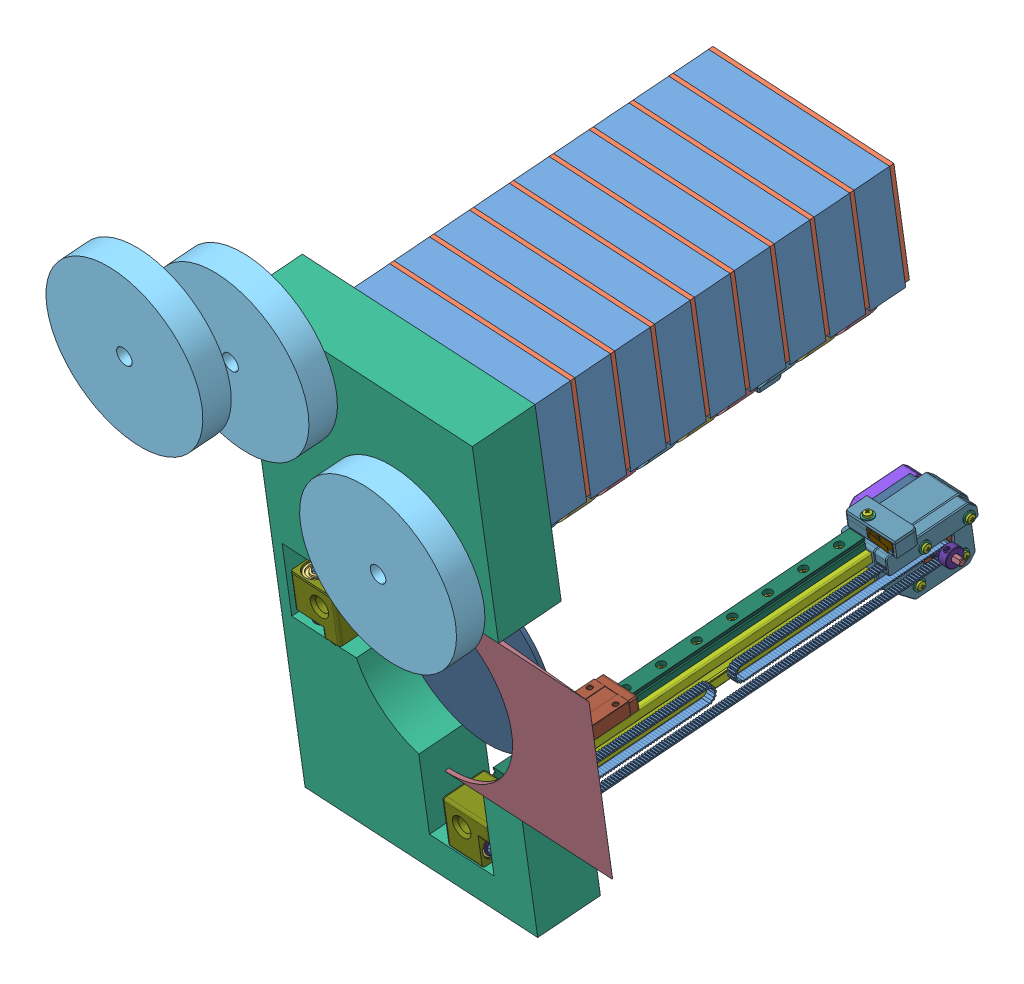
SolidWorks assembly SYSTEM2, configuration Default. Lengths in mm.
Overall size (315.85 484.95 561.42).
165 component instances, 31 part files, 110 mates.
Components (placement in the parent):
- Cakeholder-2: Cakeholder [Default] at (-409.943 623.3582 192.3225) x (0.998594 -0.003676 0.05288) z (-0.05288 -0.138263 0.988983) size (140 83.09 25)
- Cakeholder-3: Cakeholder [Default] at (-404.0205 638.8436 81.5565) x (0.998594 -0.003676 0.05288) z (-0.05288 -0.138263 0.988983) size (140 83.09 25)
- Cakeholder-4: Cakeholder [Default] at (-406.9818 631.1009 136.9395) x (0.998594 -0.003676 0.05288) z (-0.05288 -0.138263 0.988983) size (140 83.09 25)
- Cakeholder-5: Cakeholder [Default] at (-398.098 654.3291 -29.2096) x (0.998594 -0.003676 0.05288) z (-0.05288 -0.138263 0.988983) size (140 83.09 25)
- Cakeholder-6: Cakeholder [Default] at (-408.4624 627.2296 164.631) x (0.998594 -0.003676 0.05288) z (-0.05288 -0.138263 0.988983) size (140 83.09 25)
- Cakeholder-7: Cakeholder [Default] at (-405.5012 634.9723 109.248) x (0.998594 -0.003676 0.05288) z (-0.05288 -0.138263 0.988983) size (140 83.09 25)
- Cakeholder-8: Cakeholder [Default] at (-399.5786 650.4577 -1.5181) x (0.998594 -0.003676 0.05288) z (-0.05288 -0.138263 0.988983) size (140 83.09 25)
- Cakeholder-9: Cakeholder [Default] at (-401.0593 646.5864 26.1734) x (0.998594 -0.003676 0.05288) z (-0.05288 -0.138263 0.988983) size (140 83.09 25)
- Cakeholder-10: Cakeholder [Default] at (-402.5399 642.715 53.8649) x (0.998594 -0.003676 0.05288) z (-0.05288 -0.138263 0.988983) size (140 83.09 25)
- isolation-1: isolation [Default] at (-479.9507 695.3383 195.6089) x (0.998594 -0.003676 0.05288) z (-0.05288 -0.138263 0.988983) size (140 80 3)
- isolation-2: isolation [Default] at (-478.47 699.2097 167.9174) x (0.998594 -0.003676 0.05288) z (-0.05288 -0.138263 0.988983) size (140 80 3)
- isolation-3: isolation [Default] at (-476.9894 703.081 140.2259) x (0.998594 -0.003676 0.05288) z (-0.05288 -0.138263 0.988983) size (140 80 3)
- isolation-4: isolation [Default] at (-475.5088 706.9524 112.5344) x (0.998594 -0.003676 0.05288) z (-0.05288 -0.138263 0.988983) size (140 80 3)
- isolation-5: isolation [Default] at (-328.0084 646.5634 -29.5811) x (-0.998594 0.003676 -0.05288) z (-0.05288 -0.138263 0.988983) size (140 80 3)
- isolation-6: isolation [Default] at (-474.0281 710.8237 84.8429) x (0.998594 -0.003676 0.05288) z (-0.05288 -0.138263 0.988983) size (140 80 3)
- isolation-7: isolation [Default] at (-472.5475 714.6951 57.1513) x (0.998594 -0.003676 0.05288) z (-0.05288 -0.138263 0.988983) size (140 80 3)
- isolation-8: isolation [Default] at (-471.0669 718.5665 29.4598) x (0.998594 -0.003676 0.05288) z (-0.05288 -0.138263 0.988983) size (140 80 3)
- isolation-9: isolation [Default] at (-469.5863 722.4378 1.7683) x (0.998594 -0.003676 0.05288) z (-0.05288 -0.138263 0.988983) size (140 80 3)
- cream_yellow-1: cream_yellow [Default] at (-408.7268 626.5383 169.5759) x (0.998594 -0.003676 0.05288) z (-0.05288 -0.138263 0.988983) size (120 120 20)
- Icing_pink-1: Icing_pink [Default] at (-407.2462 630.4096 141.8844) x (0.998594 -0.003676 0.05288) z (-0.05288 -0.138263 0.988983) size (120 120 20)
- sponge_brown-1: sponge_brown [Default] at (-410.2074 622.6669 197.2675) x (0.992993 0.097531 0.066729) z (-0.05288 -0.138263 0.988983) size (120 120 20)
- cream_yellow-2: cream_yellow [Default] at (-404.2849 638.1523 86.5014) x (0.981304 0.176336 0.077121) z (-0.05288 -0.138263 0.988983) size (120 120 20)
- Icing_pink-2: Icing_pink [Default] at (-402.8043 642.0237 58.8099) x (0.983044 -0.181339 0.02721) z (-0.05288 -0.138263 0.988983) size (120 120 20)
- sponge_brown-2: sponge_brown [Default] at (-401.3237 645.8951 31.1183) x (0.832811 -0.552589 -0.032724) z (-0.05288 -0.138263 0.988983) size (120 120 20)
- cream_yellow-3: cream_yellow [Default] at (-399.843 649.7664 3.4268) x (0.998594 -0.003676 0.05288) z (-0.05288 -0.138263 0.988983) size (120 120 20)
- Icing_pink-3: Icing_pink [Default] at (-398.3624 653.6378 -24.2647) x (-0.229057 0.965642 0.122752) z (-0.05288 -0.138263 0.988983) size (120 120 20)
- sponge_brown-3: sponge_brown [Default] at (-405.7656 634.281 114.1929) x (0.916532 0.386462 0.103034) z (-0.05288 -0.138263 0.988983) size (120 120 20)
- base-2: base [Default] at (-384.5565 489.403 244.7212) x (0.003676 -0.990389 -0.138263) z (0.05288 0.138263 -0.988983) size (337 180 44)
- Assem1-2: Assem1 [По умолчанию] at (-489.5964 495.154 221.7084) x (-0.003676 0.990389 0.138263) z (0.05288 0.138263 -0.988983) size (62 62.45 345.25)
  - rsi_2020_274-1: rsi_2020_274 [По умолчанию] at origin size (20 20 274)
  - 17HM15-0904S-1: 17HM15-0904S [По умолчанию] at (30 -11.15 303.15) x (0 0 -1) z (0 1 0) size (42.3 62 42.3)
    - nema17_bottom_40mm-1: nema17_bottom_40mm [По умолчанию] at origin size (42 12 42)
    - radial ball bearing_68_din-1: radial ball bearing_68_din [DIN 625 - 625 - 8,SI,NC,8_68] at (0 5 0) x (0 -1 0) z (0 0 1) size (5 16 16)
    - nema17_middle_40mm-1: nema17_middle_40mm [По умолчанию] at (0 8.5 0) size (42.3 23.5 42.3)
    - nema17_top_40mm-1: nema17_top_40mm [По умолчанию] at (0 32 0) size (42.3 12.6 42.3)
    - radial ball bearing_68_din-3: radial ball bearing_68_din [DIN 625 - 625 - 8,SI,NC,8_68] at (0 38.1 0) x (0 1 0) z (0 0 1) size (5 16 16)
    - countersunk flat head cross recess screw_din-1: countersunk flat head cross recess screw_din [ISO 7046-1 - M3 x 30 - Z --- 30N] at (15.5 0.6 15.5) x (0 1 0) z (0.546944 0 -0.837169) size (30 5.5 5.5)
    - countersunk flat head cross recess screw_din-2: countersunk flat head cross recess screw_din [ISO 7046-1 - M3 x 25 - Z --- 25N] at (15.5 0.6 -15.5) x (0 1 0) z (0.546944 0 -0.837169) size (25 5.5 5.5)
    - countersunk flat head cross recess screw_din-3: countersunk flat head cross recess screw_din [ISO 7046-1 - M3 x 30 - Z --- 30N] at (-15.5 0.6 15.5) x (0 1 0) z (0.546944 0 -0.837169) size (30 5.5 5.5)
    - countersunk flat head cross recess screw_din-4: countersunk flat head cross recess screw_din [ISO 7046-1 - M3 x 30 - Z --- 30N] at (-15.5 0.6 -15.5) x (0 1 0) z (0.546944 0 -0.837169) size (30 5.5 5.5)
    - nema17_shaft_40mm-1: nema17_shaft_40mm [По умолчанию] at (0 2 0) x (-0.412738 0 0.91085) z (-0.91085 0 -0.412738) size (5 60 5)
  - nema17_mount_1-1: nema17_mount_1 [По умолчанию] at (-13 -10.7443 294.7873) x (0 0 -1) z (1 0 0) size (65.25 59.3 39.22)
  - MGN12_250-1: MGN12_250 [По умолчанию] at (0 14 12) size (12 8 250)
  - idle_pul_mount_1-1: idle_pul_mount_1 [По умолчанию] at (13 -3.403 -4.0666) x (0 0 1) z (-1 0 0) size (30 34 35)
  - GT2_16T_13x14-1: GT2_16T_13x14 [Конфигурация1] at (-26.5 -11.15 303.15) x (1 0 0) z (0 0.386253 0.922393) size (14.1 13 13)
  - GT2_16T_13x14-2: GT2_16T_13x14 [Конфигурация1] at (-26.5 -11.15 -8.1562) x (1 0 0) z (0 0.133178 -0.991092) size (14.1 13 13)
  - SS-5GL_microswitch-2: SS-5GL_microswitch [Default] at (-42.2883 22.25 275.1397) x (0 -1 0) z (1 0 0) size (6.5 17.14 19.7)
  - belt_250-1: belt_250 [По умолчанию] at (-19.83 -1.6143 147.7424) size (6 22.27 322.67)
  - mgn12_fix-1: mgn12_fix [По умолчанию] at (0 12.9786 54.5) x (1 0 0) z (0 1 0) size (9.5 35 6)
  - mgn12_fix-2: mgn12_fix [По умолчанию] at (0 12.9786 104.5) x (1 0 0) z (0 1 0) size (9.5 35 6)
  - mgn12_fix-3: mgn12_fix [По умолчанию] at (0 12.9786 254.5) x (1 0 0) z (0 1 0) size (9.5 35 6)
  - mgn12_fix-4: mgn12_fix [По умолчанию] at (0 12.9786 154.5) x (1 0 0) z (0 1 0) size (9.5 35 6)
  - mgn12_fix-5: mgn12_fix [По умолчанию] at (0 12.9786 204.5) x (1 0 0) z (0 1 0) size (9.5 35 6)
  - instrument ball bearing_68_am-1: instrument ball bearing_68_am [AFBMA 12.1.4.1 - 0050-16 - 8,SI,NC,8_68] at (-9.5 -11.15 -8.1562) size (5 16 16)
  - instrument ball bearing_68_am-2: instrument ball bearing_68_am [AFBMA 12.1.4.1 - 0050-16 - 8,SI,NC,8_68] at (9.5 -11.15 -8.1562) size (5 16 16)
  - socket head cap screw_am-1: socket head cap screw_am [B18.3.1M - 5 x 0.8 x 20 Hex SHCS -- 20NHX] at (0 0 280.85) x (0 0 -1) z (1 0 0) size (25 8.5 8.5)
  - socket head cap screw_am-2: socket head cap screw_am [B18.3.1M - 5 x 0.8 x 20 Hex SHCS -- 20NHX] at (0 0 -11) x (0 0 1) z (-1 0 0) size (25 8.5 8.5)
  - continous stud_am-1: continous stud_am [AM -- M5 x 45  N] at (-31 -11.15 -8.1562) size (45 5 5)
  - plain washer 6902 type abc_din-1: plain washer 6902 type abc_din [DIN 6902-A3.2] at (-13 -26.65 318.65) x (-1 0 0) z (0 0.924225 0.381849) size (0.8 8 8)
  - pan head cross recess screw_din-4: pan head cross recess screw_din [ISO 7045 - M3 x 6 - Z --- 6N] at (-16.2 -26.65 318.65) size (8.35 5.6 5.6)
  - pan head cross recess screw_din-5: pan head cross recess screw_din [ISO 7045 - M3 x 6 - Z --- 6N] at (-16.2 -26.65 287.65) size (8.35 5.6 5.6)
  - plain washer 6902 type abc_din-2: plain washer 6902 type abc_din [DIN 6902-A3.2] at (-13 -26.65 287.65) x (-1 0 0) z (0 0.924225 0.381849) size (0.8 8 8)
  - pan head cross recess screw_din-6: pan head cross recess screw_din [ISO 7045 - M3 x 16 - Z --- 16N] at (-25.2 4.35 287.65) size (18.35 5.6 5.6)
  - plain washer 6902 type abc_din-3: plain washer 6902 type abc_din [DIN 6902-A3.2] at (-22 4.35 287.65) x (-1 0 0) z (0 0.924225 0.381849) size (0.8 8 8)
  - plain washer 6902 type abc_din-4: plain washer 6902 type abc_din [DIN 6902-A3.2] at (-22 4.35 318.65) x (-1 0 0) z (0 0.924225 0.381849) size (0.8 8 8)
  - pan head cross recess screw_din-7: pan head cross recess screw_din [ISO 7045 - M3 x 20 - Z --- 20N] at (-25.2 4.35 318.65) size (22.35 5.6 5.6)
  - pan head cross recess screw_din-9: pan head cross recess screw_din [ISO 7045 - M3 x 8 - Z --- 8N] at (0 15.9 24.5) x (0 -1 0) z (0 0 1) size (10.35 5.6 5.6)
  - pan head cross recess screw_din-10: pan head cross recess screw_din [ISO 7045 - M3 x 8 - Z --- 8N] at (0 15.9 49.5) x (0 -1 0) z (-0.931961 0 -0.362559) size (10.35 5.6 5.6)
  - hex nut style 1 gradeab_din-1: hex nut style 1 gradeab_din [Hexagon Nut ISO 4032 - M3 - D - N] at (0 5.1 24.5) x (0.5 0 0.866025) z (0 -1 0) size (5.5 6.35 2.4)
  - hex nut style 1 gradeab_din-2: hex nut style 1 gradeab_din [Hexagon Nut ISO 4032 - M3 - D - N] at (0 5.1 49.5) x (0.5 0 0.866025) z (0 -1 0) size (5.5 6.35 2.4)
  - hex nut style 1 gradeab_din-3: hex nut style 1 gradeab_din [Hexagon Nut ISO 4032 - M3 - D - N] at (0 5.1 99.5) x (0.5 0 0.866025) z (0 -1 0) size (5.5 6.35 2.4)
  - hex nut style 1 gradeab_din-4: hex nut style 1 gradeab_din [Hexagon Nut ISO 4032 - M3 - D - N] at (0 5.1 74.5) x (0.5 0 0.866025) z (0 -1 0) size (5.5 6.35 2.4)
  - pan head cross recess screw_din-11: pan head cross recess screw_din [ISO 7045 - M3 x 8 - Z --- 8N] at (0 15.9 74.5) x (0 -1 0) z (0 0 1) size (10.35 5.6 5.6)
  - pan head cross recess screw_din-12: pan head cross recess screw_din [ISO 7045 - M3 x 8 - Z --- 8N] at (0 15.9 99.5) x (0 -1 0) z (-0.931961 0 -0.362559) size (10.35 5.6 5.6)
  - hex nut style 1 gradeab_din-5: hex nut style 1 gradeab_din [Hexagon Nut ISO 4032 - M3 - D - N] at (0 5.1 249.5) x (0.5 0 0.866025) z (0 -1 0) size (5.5 6.35 2.4)
  - hex nut style 1 gradeab_din-6: hex nut style 1 gradeab_din [Hexagon Nut ISO 4032 - M3 - D - N] at (0 5.1 224.5) x (0.5 0 0.866025) z (0 -1 0) size (5.5 6.35 2.4)
  - pan head cross recess screw_din-13: pan head cross recess screw_din [ISO 7045 - M3 x 8 - Z --- 8N] at (0 15.9 224.5) x (0 -1 0) z (0 0 1) size (10.35 5.6 5.6)
  - pan head cross recess screw_din-14: pan head cross recess screw_din [ISO 7045 - M3 x 8 - Z --- 8N] at (0 15.9 249.5) x (0 -1 0) z (-0.931961 0 -0.362559) size (10.35 5.6 5.6)
  - hex nut style 1 gradeab_din-7: hex nut style 1 gradeab_din [Hexagon Nut ISO 4032 - M3 - D - N] at (0 5.1 149.5) x (0.5 0 0.866025) z (0 -1 0) size (5.5 6.35 2.4)
  - hex nut style 1 gradeab_din-8: hex nut style 1 gradeab_din [Hexagon Nut ISO 4032 - M3 - D - N] at (0 5.1 124.5) x (0.5 0 0.866025) z (0 -1 0) size (5.5 6.35 2.4)
  - pan head cross recess screw_din-15: pan head cross recess screw_din [ISO 7045 - M3 x 8 - Z --- 8N] at (0 15.9 124.5) x (0 -1 0) z (0 0 1) size (10.35 5.6 5.6)
  - pan head cross recess screw_din-16: pan head cross recess screw_din [ISO 7045 - M3 x 8 - Z --- 8N] at (0 15.9 149.5) x (0 -1 0) z (-0.931961 0 -0.362559) size (10.35 5.6 5.6)
  - hex nut style 1 gradeab_din-9: hex nut style 1 gradeab_din [Hexagon Nut ISO 4032 - M3 - D - N] at (0 5.1 199.5) x (0.5 0 0.866025) z (0 -1 0) size (5.5 6.35 2.4)
  - hex nut style 1 gradeab_din-10: hex nut style 1 gradeab_din [Hexagon Nut ISO 4032 - M3 - D - N] at (0 5.1 174.5) x (0.5 0 0.866025) z (0 -1 0) size (5.5 6.35 2.4)
  - pan head cross recess screw_din-17: pan head cross recess screw_din [ISO 7045 - M3 x 8 - Z --- 8N] at (0 15.9 174.5) x (0 -1 0) z (0 0 1) size (10.35 5.6 5.6)
  - pan head cross recess screw_din-18: pan head cross recess screw_din [ISO 7045 - M3 x 8 - Z --- 8N] at (0 15.9 199.5) x (0 -1 0) z (-0.931961 0 -0.362559) size (10.35 5.6 5.6)
  - plain washer 6902 type abc_din-5: plain washer 6902 type abc_din [DIN 6902-A3.2] at (0 24 270.6521) x (0 1 0) z (0.924225 0 0.381849) size (0.8 8 8)
  - pan head cross recess screw_din-23: pan head cross recess screw_din [ISO 7045 - M3 x 16 - Z --- 16N] at (0 27.2 270.6521) x (0 -1 0) z (0 0 1) size (18.35 5.6 5.6)
- pan head cross recess screw_din-4: pan head cross recess screw_din [ISO 7045 - M3 x 16 - Z --- 16N] at (-486.5703 494.0274 150.3004) x (0.003676 -0.990389 -0.138263) z (-0.191075 -0.136412 0.97205) size (18.35 5.6 5.6)
- pan head cross recess screw_din-5: pan head cross recess screw_din [ISO 7045 - M3 x 16 - Z --- 16N] at (-487.8923 490.5708 175.025) x (0.003676 -0.990389 -0.138263) z (0.138263 -0.136432 0.980953) size (18.35 5.6 5.6)
- prevailing torque nut style 1 insert_din-2: prevailing torque nut style 1 insert_din [DIN EN ISO 7040 - M3 - N] at (-487.837 475.6654 172.9442) x (0.701337 0.101111 -0.705623) z (0.003676 -0.990389 -0.138263) size (5.5 6.35 4.5)
- prevailing torque nut style 1 insert_din-3: prevailing torque nut style 1 insert_din [DIN EN ISO 7040 - M3 - N] at (-486.515 479.122 148.2196) x (-0.138263 0.136432 -0.980953) z (0.003676 -0.990389 -0.138263) size (5.5 6.35 4.5)
- alum_40x40x2-1-1: alum_40x40x2-1 [По умолчанию] at (-462.417 484.1818 142.6319) x (-0.05288 -0.138263 0.988983) z (-0.998594 0.003676 -0.05288) size (66.69 120 160)
- MGN12-H-1-1: MGN12-H-1 [По умолчанию] at (-468.5481 503.1244 165.1751) x (0.003676 -0.990389 -0.138263) z (-0.05288 -0.138263 0.988983) size (27 10 45.19)
- pan head cross recess screw_din-7: pan head cross recess screw_din [ISO 7045 - M3 x 6 - Z --- 6N] at (-458.6693 514.3764 157.165) x (-0.998594 0.003676 -0.05288) z (0.052472 -0.07286 -0.995961) size (8.35 5.6 5.6)
- pan head cross recess screw_din-8: pan head cross recess screw_din [ISO 7045 - M3 x 6 - Z --- 6N] at (-459.7269 511.6111 176.9446) x (-0.998594 0.003676 -0.05288) z (-0.05124 -0.322389 0.945219) size (8.35 5.6 5.6)
- pan head cross recess screw_din-9: pan head cross recess screw_din [ISO 7045 - M3 x 6 - Z --- 6N] at (-459.6533 491.8034 174.1794) x (-0.998594 0.003676 -0.05288) z (0.052886 0.001609 -0.998599) size (8.35 5.6 5.6)
- pan head cross recess screw_din-10: pan head cross recess screw_din [ISO 7045 - M3 x 6 - Z --- 6N] at (-458.5958 494.5686 154.3997) x (-0.998594 0.003676 -0.05288) z (0.047339 -0.387009 -0.92086) size (8.35 5.6 5.6)
- idle_pulley_16-1-3: idle_pulley_16-1 [По умолчанию] at (-487.8651 483.2579 174.0041) x (0.990389 0.022722 -0.136432) z (0.138263 -0.136432 0.980953) size (13 9 13)
- idle_pulley_16-1-4: idle_pulley_16-1 [По умолчанию] at (-486.5432 486.7145 149.2795) x (0.96048 -0.034986 0.276141) z (-0.278324 -0.133814 0.95112) size (13 9 13)
- MGN12-H-1-2: MGN12-H-1 [По умолчанию] at (-390.0014 427.4349 142.5158) x (0.998594 -0.003676 0.05288) z (-0.05288 -0.138263 0.988983) size (27 10 45.19)
- Assem1-4: Assem1 [По умолчанию] at (-393.8602 399.3455 213.433) x (-0.998594 0.003676 -0.05288) z (0.05288 0.138263 -0.988983) size (62 62.45 345.25)
  - rsi_2020_274-1: rsi_2020_274 [По умолчанию] at origin size (20 20 274)
  - 17HM15-0904S-1: 17HM15-0904S [По умолчанию] at (30 -11.15 303.15) x (0 0 -1) z (0 1 0) size (42.3 62 42.3)
    - nema17_bottom_40mm-1: nema17_bottom_40mm [По умолчанию] at origin size (42 12 42)
    - radial ball bearing_68_din-1: radial ball bearing_68_din [DIN 625 - 625 - 8,SI,NC,8_68] at (0 5 0) x (0 -1 0) z (0 0 1) size (5 16 16)
    - nema17_middle_40mm-1: nema17_middle_40mm [По умолчанию] at (0 8.5 0) size (42.3 23.5 42.3)
    - nema17_top_40mm-1: nema17_top_40mm [По умолчанию] at (0 32 0) size (42.3 12.6 42.3)
    - radial ball bearing_68_din-3: radial ball bearing_68_din [DIN 625 - 625 - 8,SI,NC,8_68] at (0 38.1 0) x (0 1 0) z (0 0 1) size (5 16 16)
    - countersunk flat head cross recess screw_din-1: countersunk flat head cross recess screw_din [ISO 7046-1 - M3 x 30 - Z --- 30N] at (15.5 0.6 15.5) x (0 1 0) z (0.546944 0 -0.837169) size (30 5.5 5.5)
    - countersunk flat head cross recess screw_din-2: countersunk flat head cross recess screw_din [ISO 7046-1 - M3 x 25 - Z --- 25N] at (15.5 0.6 -15.5) x (0 1 0) z (0.546944 0 -0.837169) size (25 5.5 5.5)
    - countersunk flat head cross recess screw_din-3: countersunk flat head cross recess screw_din [ISO 7046-1 - M3 x 30 - Z --- 30N] at (-15.5 0.6 15.5) x (0 1 0) z (0.546944 0 -0.837169) size (30 5.5 5.5)
    - countersunk flat head cross recess screw_din-4: countersunk flat head cross recess screw_din [ISO 7046-1 - M3 x 30 - Z --- 30N] at (-15.5 0.6 -15.5) x (0 1 0) z (0.546944 0 -0.837169) size (30 5.5 5.5)
    - nema17_shaft_40mm-1: nema17_shaft_40mm [По умолчанию] at (0 2 0) x (-0.412738 0 0.91085) z (-0.91085 0 -0.412738) size (5 60 5)
  - nema17_mount_1-1: nema17_mount_1 [По умолчанию] at (-13 -10.7443 294.7873) x (0 0 -1) z (1 0 0) size (65.25 59.3 39.22)
  - MGN12_250-1: MGN12_250 [По умолчанию] at (0 14 12) size (12 8 250)
  - idle_pul_mount_1-1: idle_pul_mount_1 [По умолчанию] at (13 -3.403 -4.0666) x (0 0 1) z (-1 0 0) size (30 34 35)
  - GT2_16T_13x14-1: GT2_16T_13x14 [Конфигурация1] at (-26.5 -11.15 303.15) x (1 0 0) z (0 0.386253 0.922393) size (14.1 13 13)
  - GT2_16T_13x14-2: GT2_16T_13x14 [Конфигурация1] at (-26.5 -11.15 -8.1562) x (1 0 0) z (0 0.133178 -0.991092) size (14.1 13 13)
  - SS-5GL_microswitch-2: SS-5GL_microswitch [Default] at (-42.2883 22.25 275.1397) x (0 -1 0) z (1 0 0) size (6.5 17.14 19.7)
  - belt_250-1: belt_250 [По умолчанию] at (-19.83 -1.6143 147.7424) size (6 22.27 322.67)
  - mgn12_fix-1: mgn12_fix [По умолчанию] at (0 12.9786 54.5) x (1 0 0) z (0 1 0) size (9.5 35 6)
  - mgn12_fix-2: mgn12_fix [По умолчанию] at (0 12.9786 104.5) x (1 0 0) z (0 1 0) size (9.5 35 6)
  - mgn12_fix-3: mgn12_fix [По умолчанию] at (0 12.9786 254.5) x (1 0 0) z (0 1 0) size (9.5 35 6)
  - mgn12_fix-4: mgn12_fix [По умолчанию] at (0 12.9786 154.5) x (1 0 0) z (0 1 0) size (9.5 35 6)
  - mgn12_fix-5: mgn12_fix [По умолчанию] at (0 12.9786 204.5) x (1 0 0) z (0 1 0) size (9.5 35 6)
  - instrument ball bearing_68_am-1: instrument ball bearing_68_am [AFBMA 12.1.4.1 - 0050-16 - 8,SI,NC,8_68] at (-9.5 -11.15 -8.1562) size (5 16 16)
  - instrument ball bearing_68_am-2: instrument ball bearing_68_am [AFBMA 12.1.4.1 - 0050-16 - 8,SI,NC,8_68] at (9.5 -11.15 -8.1562) size (5 16 16)
  - socket head cap screw_am-1: socket head cap screw_am [B18.3.1M - 5 x 0.8 x 20 Hex SHCS -- 20NHX] at (0 0 280.85) x (0 0 -1) z (1 0 0) size (25 8.5 8.5)
  - socket head cap screw_am-2: socket head cap screw_am [B18.3.1M - 5 x 0.8 x 20 Hex SHCS -- 20NHX] at (0 0 -11) x (0 0 1) z (-1 0 0) size (25 8.5 8.5)
  - continous stud_am-1: continous stud_am [AM -- M5 x 45  N] at (-31 -11.15 -8.1562) size (45 5 5)
  - plain washer 6902 type abc_din-1: plain washer 6902 type abc_din [DIN 6902-A3.2] at (-13 -26.65 318.65) x (-1 0 0) z (0 0.924225 0.381849) size (0.8 8 8)
  - pan head cross recess screw_din-4: pan head cross recess screw_din [ISO 7045 - M3 x 6 - Z --- 6N] at (-16.2 -26.65 318.65) size (8.35 5.6 5.6)
  - pan head cross recess screw_din-5: pan head cross recess screw_din [ISO 7045 - M3 x 6 - Z --- 6N] at (-16.2 -26.65 287.65) size (8.35 5.6 5.6)
  - plain washer 6902 type abc_din-2: plain washer 6902 type abc_din [DIN 6902-A3.2] at (-13 -26.65 287.65) x (-1 0 0) z (0 0.924225 0.381849) size (0.8 8 8)
  - pan head cross recess screw_din-6: pan head cross recess screw_din [ISO 7045 - M3 x 16 - Z --- 16N] at (-25.2 4.35 287.65) size (18.35 5.6 5.6)
  - plain washer 6902 type abc_din-3: plain washer 6902 type abc_din [DIN 6902-A3.2] at (-22 4.35 287.65) x (-1 0 0) z (0 0.924225 0.381849) size (0.8 8 8)
  - plain washer 6902 type abc_din-4: plain washer 6902 type abc_din [DIN 6902-A3.2] at (-22 4.35 318.65) x (-1 0 0) z (0 0.924225 0.381849) size (0.8 8 8)
  - pan head cross recess screw_din-7: pan head cross recess screw_din [ISO 7045 - M3 x 20 - Z --- 20N] at (-25.2 4.35 318.65) size (22.35 5.6 5.6)
  - pan head cross recess screw_din-9: pan head cross recess screw_din [ISO 7045 - M3 x 8 - Z --- 8N] at (0 15.9 24.5) x (0 -1 0) z (0 0 1) size (10.35 5.6 5.6)
  - pan head cross recess screw_din-10: pan head cross recess screw_din [ISO 7045 - M3 x 8 - Z --- 8N] at (0 15.9 49.5) x (0 -1 0) z (-0.931961 0 -0.362559) size (10.35 5.6 5.6)
  - hex nut style 1 gradeab_din-1: hex nut style 1 gradeab_din [Hexagon Nut ISO 4032 - M3 - D - N] at (0 5.1 24.5) x (0.5 0 0.866025) z (0 -1 0) size (5.5 6.35 2.4)
  - hex nut style 1 gradeab_din-2: hex nut style 1 gradeab_din [Hexagon Nut ISO 4032 - M3 - D - N] at (0 5.1 49.5) x (0.5 0 0.866025) z (0 -1 0) size (5.5 6.35 2.4)
  - hex nut style 1 gradeab_din-3: hex nut style 1 gradeab_din [Hexagon Nut ISO 4032 - M3 - D - N] at (0 5.1 99.5) x (0.5 0 0.866025) z (0 -1 0) size (5.5 6.35 2.4)
  - hex nut style 1 gradeab_din-4: hex nut style 1 gradeab_din [Hexagon Nut ISO 4032 - M3 - D - N] at (0 5.1 74.5) x (0.5 0 0.866025) z (0 -1 0) size (5.5 6.35 2.4)
  - pan head cross recess screw_din-11: pan head cross recess screw_din [ISO 7045 - M3 x 8 - Z --- 8N] at (0 15.9 74.5) x (0 -1 0) z (0 0 1) size (10.35 5.6 5.6)
  - pan head cross recess screw_din-12: pan head cross recess screw_din [ISO 7045 - M3 x 8 - Z --- 8N] at (0 15.9 99.5) x (0 -1 0) z (-0.931961 0 -0.362559) size (10.35 5.6 5.6)
  - hex nut style 1 gradeab_din-5: hex nut style 1 gradeab_din [Hexagon Nut ISO 4032 - M3 - D - N] at (0 5.1 249.5) x (0.5 0 0.866025) z (0 -1 0) size (5.5 6.35 2.4)
  - hex nut style 1 gradeab_din-6: hex nut style 1 gradeab_din [Hexagon Nut ISO 4032 - M3 - D - N] at (0 5.1 224.5) x (0.5 0 0.866025) z (0 -1 0) size (5.5 6.35 2.4)
  - pan head cross recess screw_din-13: pan head cross recess screw_din [ISO 7045 - M3 x 8 - Z --- 8N] at (0 15.9 224.5) x (0 -1 0) z (0 0 1) size (10.35 5.6 5.6)
  - pan head cross recess screw_din-14: pan head cross recess screw_din [ISO 7045 - M3 x 8 - Z --- 8N] at (0 15.9 249.5) x (0 -1 0) z (-0.931961 0 -0.362559) size (10.35 5.6 5.6)
  - hex nut style 1 gradeab_din-7: hex nut style 1 gradeab_din [Hexagon Nut ISO 4032 - M3 - D - N] at (0 5.1 149.5) x (0.5 0 0.866025) z (0 -1 0) size (5.5 6.35 2.4)
  - hex nut style 1 gradeab_din-8: hex nut style 1 gradeab_din [Hexagon Nut ISO 4032 - M3 - D - N] at (0 5.1 124.5) x (0.5 0 0.866025) z (0 -1 0) size (5.5 6.35 2.4)
  - pan head cross recess screw_din-15: pan head cross recess screw_din [ISO 7045 - M3 x 8 - Z --- 8N] at (0 15.9 124.5) x (0 -1 0) z (0 0 1) size (10.35 5.6 5.6)
  - pan head cross recess screw_din-16: pan head cross recess screw_din [ISO 7045 - M3 x 8 - Z --- 8N] at (0 15.9 149.5) x (0 -1 0) z (-0.931961 0 -0.362559) size (10.35 5.6 5.6)
  - hex nut style 1 gradeab_din-9: hex nut style 1 gradeab_din [Hexagon Nut ISO 4032 - M3 - D - N] at (0 5.1 199.5) x (0.5 0 0.866025) z (0 -1 0) size (5.5 6.35 2.4)
  - hex nut style 1 gradeab_din-10: hex nut style 1 gradeab_din [Hexagon Nut ISO 4032 - M3 - D - N] at (0 5.1 174.5) x (0.5 0 0.866025) z (0 -1 0) size (5.5 6.35 2.4)
  - pan head cross recess screw_din-17: pan head cross recess screw_din [ISO 7045 - M3 x 8 - Z --- 8N] at (0 15.9 174.5) x (0 -1 0) z (0 0 1) size (10.35 5.6 5.6)
  - pan head cross recess screw_din-18: pan head cross recess screw_din [ISO 7045 - M3 x 8 - Z --- 8N] at (0 15.9 199.5) x (0 -1 0) z (-0.931961 0 -0.362559) size (10.35 5.6 5.6)
  - plain washer 6902 type abc_din-5: plain washer 6902 type abc_din [DIN 6902-A3.2] at (0 24 270.6521) x (0 1 0) z (0.924225 0 0.381849) size (0.8 8 8)
  - pan head cross recess screw_din-23: pan head cross recess screw_din [ISO 7045 - M3 x 16 - Z --- 16N] at (0 27.2 270.6521) x (0 -1 0) z (0 0 1) size (18.35 5.6 5.6)
- slider-1: slider [Default] at (-402.9913 491.3879 240.9796) x (-0.998594 0.003676 -0.05288) z (-0.05288 -0.138263 0.988983) size (130 122 3)
- sponge_brown-4: sponge_brown [Default] at (-438.4367 776.4176 413.4929) x (0.998594 -0.003676 0.05288) z (-0.05288 -0.138263 0.988983) size (120 120 20)
- sponge_brown-5: sponge_brown [Default] at (-405.1668 767.3344 369.1351) x (0.998594 -0.003676 0.05288) z (-0.05288 -0.138263 0.988983) size (120 120 20)
- sponge_brown-6: sponge_brown [Default] at (-270.1939 713.9476 396.1545) x (0.998594 -0.003676 0.05288) z (-0.05288 -0.138263 0.988983) size (120 120 20)
Mates (geometry in assembly coordinates):
- Coincident75: coincident anti-aligned: plane of Cakeholder-5 through (-398.098 654.3291 -29.2096) normal (0.05288 0.138263 -0.988983); plane of isolation-5 through (-328.167 646.1487 -26.6142) normal (-0.05288 -0.138263 0.988983)
- Coincident77: coincident anti-aligned: plane of Cakeholder-5 through (-399.42 650.8725 -4.4851) normal (-0.05288 -0.138263 0.988983); plane of isolation-9 through (-469.5863 722.4378 1.7683) normal (0.05288 0.138263 -0.988983)
- Coincident78: coincident anti-aligned: plane of Cakeholder-8 through (-399.5786 650.4577 -1.5181) normal (0.05288 0.138263 -0.988983); plane of isolation-9 through (-469.7449 722.023 4.7353) normal (-0.05288 -0.138263 0.988983)
- Coincident79: coincident anti-aligned: plane of Cakeholder-8 through (-400.9006 647.0012 23.2065) normal (-0.05288 -0.138263 0.988983); plane of isolation-8 through (-471.0669 718.5665 29.4598) normal (0.05288 0.138263 -0.988983)
- Coincident80: coincident anti-aligned: plane of Cakeholder-9 through (-401.0593 646.5864 26.1734) normal (0.05288 0.138263 -0.988983); plane of isolation-8 through (-471.2255 718.1517 32.4268) normal (-0.05288 -0.138263 0.988983)
- Coincident81: coincident anti-aligned: plane of Cakeholder-9 through (-402.3813 643.1298 50.898) normal (-0.05288 -0.138263 0.988983); plane of isolation-7 through (-472.5475 714.6951 57.1513) normal (0.05288 0.138263 -0.988983)
- Coincident82: coincident anti-aligned: plane of Cakeholder-10 through (-402.5399 642.715 53.8649) normal (0.05288 0.138263 -0.988983); plane of isolation-7 through (-472.7062 714.2803 60.1183) normal (-0.05288 -0.138263 0.988983)
- Coincident83: coincident anti-aligned: plane of Cakeholder-10 through (-403.8619 639.2584 78.5895) normal (-0.05288 -0.138263 0.988983); plane of isolation-6 through (-474.0281 710.8237 84.8429) normal (0.05288 0.138263 -0.988983)
- Coincident84: coincident anti-aligned: plane of Cakeholder-3 through (-404.0205 638.8436 81.5565) normal (0.05288 0.138263 -0.988983); plane of isolation-6 through (-474.1868 710.409 87.8098) normal (-0.05288 -0.138263 0.988983)
- Coincident85: coincident anti-aligned: plane of Cakeholder-3 through (-405.3425 635.3871 106.281) normal (-0.05288 -0.138263 0.988983); plane of isolation-4 through (-475.5088 706.9524 112.5344) normal (0.05288 0.138263 -0.988983)
- Coincident86: coincident anti-aligned: plane of Cakeholder-7 through (-405.5012 634.9723 109.248) normal (0.05288 0.138263 -0.988983); plane of isolation-4 through (-475.6674 706.5376 115.5013) normal (-0.05288 -0.138263 0.988983)
- Coincident87: coincident anti-aligned: plane of Cakeholder-7 through (-406.8231 631.5157 133.9726) normal (-0.05288 -0.138263 0.988983); plane of isolation-3 through (-476.9894 703.081 140.2259) normal (0.05288 0.138263 -0.988983)
- Coincident88: coincident anti-aligned: plane of Cakeholder-4 through (-406.9818 631.1009 136.9395) normal (0.05288 0.138263 -0.988983); plane of isolation-3 through (-477.148 702.6662 143.1929) normal (-0.05288 -0.138263 0.988983)
- Coincident89: coincident anti-aligned: plane of Cakeholder-4 through (-408.3038 627.6444 161.6641) normal (-0.05288 -0.138263 0.988983); plane of isolation-2 through (-478.47 699.2097 167.9174) normal (0.05288 0.138263 -0.988983)
- Coincident90: coincident anti-aligned: plane of Cakeholder-6 through (-408.4624 627.2296 164.631) normal (0.05288 0.138263 -0.988983); plane of isolation-2 through (-478.6287 698.7949 170.8844) normal (-0.05288 -0.138263 0.988983)
- Coincident91: coincident anti-aligned: plane of Cakeholder-6 through (-409.7844 623.773 189.3556) normal (-0.05288 -0.138263 0.988983); plane of isolation-1 through (-479.9507 695.3383 195.6089) normal (0.05288 0.138263 -0.988983)
- Coincident92: coincident anti-aligned: plane of Cakeholder-2 through (-409.943 623.3582 192.3225) normal (0.05288 0.138263 -0.988983); plane of isolation-1 through (-480.1093 694.9235 198.5759) normal (-0.05288 -0.138263 0.988983)
- Coincident95: coincident aligned: plane of Cakeholder-2 through (-481.4313 691.4669 223.3005) normal (-0.003676 0.990389 0.138263); plane of isolation-1 through (-480.1093 694.9235 198.5759) normal (-0.003676 0.990389 0.138263)
- Coincident96: coincident aligned: plane of Cakeholder-2 through (-481.4313 691.4669 223.3005) normal (-0.003676 0.990389 0.138263); plane of Cakeholder-6 through (-479.9507 695.3383 195.6089) normal (-0.003676 0.990389 0.138263)
- Coincident97: coincident aligned: plane of Cakeholder-2 through (-481.4313 691.4669 223.3005) normal (-0.003676 0.990389 0.138263); plane of isolation-2 through (-478.6287 698.7949 170.8844) normal (-0.003676 0.990389 0.138263)
- Coincident98: coincident aligned: plane of Cakeholder-2 through (-481.4313 691.4669 223.3005) normal (-0.003676 0.990389 0.138263); plane of Cakeholder-4 through (-478.47 699.2097 167.9174) normal (-0.003676 0.990389 0.138263)
- Coincident99: coincident aligned: plane of Cakeholder-2 through (-481.4313 691.4669 223.3005) normal (-0.003676 0.990389 0.138263); plane of isolation-3 through (-477.148 702.6662 143.1929) normal (-0.003676 0.990389 0.138263)
- Coincident100: coincident aligned: plane of Cakeholder-2 through (-481.4313 691.4669 223.3005) normal (-0.003676 0.990389 0.138263); plane of Cakeholder-7 through (-476.9894 703.081 140.2259) normal (-0.003676 0.990389 0.138263)
- Coincident101: coincident aligned: plane of Cakeholder-2 through (-481.4313 691.4669 223.3005) normal (-0.003676 0.990389 0.138263); plane of isolation-4 through (-475.6674 706.5376 115.5013) normal (-0.003676 0.990389 0.138263)
- Coincident102: coincident aligned: plane of Cakeholder-2 through (-481.4313 691.4669 223.3005) normal (-0.003676 0.990389 0.138263); plane of Cakeholder-3 through (-475.5088 706.9524 112.5344) normal (-0.003676 0.990389 0.138263)
- Coincident103: coincident aligned: plane of Cakeholder-2 through (-481.4313 691.4669 223.3005) normal (-0.003676 0.990389 0.138263); plane of isolation-6 through (-474.1868 710.409 87.8098) normal (-0.003676 0.990389 0.138263)
- Coincident104: coincident aligned: plane of Cakeholder-2 through (-481.4313 691.4669 223.3005) normal (-0.003676 0.990389 0.138263); plane of Cakeholder-10 through (-474.0281 710.8237 84.8429) normal (-0.003676 0.990389 0.138263)
- Coincident105: coincident aligned: plane of Cakeholder-2 through (-481.4313 691.4669 223.3005) normal (-0.003676 0.990389 0.138263); plane of isolation-7 through (-472.7062 714.2803 60.1183) normal (-0.003676 0.990389 0.138263)
- Coincident106: coincident aligned: plane of Cakeholder-2 through (-481.4313 691.4669 223.3005) normal (-0.003676 0.990389 0.138263); plane of Cakeholder-9 through (-472.5475 714.6951 57.1513) normal (-0.003676 0.990389 0.138263)
- Coincident107: coincident aligned: plane of Cakeholder-2 through (-481.4313 691.4669 223.3005) normal (-0.003676 0.990389 0.138263); plane of isolation-8 through (-471.2255 718.1517 32.4268) normal (-0.003676 0.990389 0.138263)
- Coincident108: coincident aligned: plane of Cakeholder-2 through (-481.4313 691.4669 223.3005) normal (-0.003676 0.990389 0.138263); plane of Cakeholder-8 through (-471.0669 718.5665 29.4598) normal (-0.003676 0.990389 0.138263)
- Coincident109: coincident aligned: plane of Cakeholder-2 through (-481.4313 691.4669 223.3005) normal (-0.003676 0.990389 0.138263); plane of isolation-9 through (-469.7449 722.023 4.7353) normal (-0.003676 0.990389 0.138263)
- Coincident110: coincident aligned: plane of Cakeholder-2 through (-481.4313 691.4669 223.3005) normal (-0.003676 0.990389 0.138263); plane of Cakeholder-5 through (-469.5863 722.4378 1.7683) normal (-0.003676 0.990389 0.138263)
- Coincident111: coincident aligned: plane of Cakeholder-2 through (-481.4313 691.4669 223.3005) normal (-0.003676 0.990389 0.138263); plane of isolation-5 through (-328.4611 725.3798 -15.5531) normal (-0.003676 0.990389 0.138263)
- Coincident112: coincident aligned: plane of Cakeholder-2 through (-341.6281 690.9523 230.7036) normal (0.998594 -0.003676 0.05288); plane of isolation-1 through (-340.3061 694.4089 205.979) normal (0.998594 -0.003676 0.05288)
- Coincident113: coincident aligned: plane of Cakeholder-2 through (-341.6281 690.9523 230.7036) normal (0.998594 -0.003676 0.05288); plane of Cakeholder-6 through (-340.1475 694.8237 203.0121) normal (0.998594 -0.003676 0.05288)
- Coincident114: coincident aligned: plane of Cakeholder-2 through (-341.6281 690.9523 230.7036) normal (0.998594 -0.003676 0.05288); plane of isolation-2 through (-338.8255 698.2803 178.2875) normal (0.998594 -0.003676 0.05288)
- Coincident115: coincident aligned: plane of Cakeholder-2 through (-341.6281 690.9523 230.7036) normal (0.998594 -0.003676 0.05288); plane of Cakeholder-4 through (-338.6668 698.695 175.3206) normal (0.998594 -0.003676 0.05288)
- Coincident116: coincident aligned: plane of Cakeholder-2 through (-341.6281 690.9523 230.7036) normal (0.998594 -0.003676 0.05288); plane of isolation-3 through (-337.3449 702.1516 150.596) normal (0.998594 -0.003676 0.05288)
- Coincident117: coincident aligned: plane of Cakeholder-2 through (-341.6281 690.9523 230.7036) normal (0.998594 -0.003676 0.05288); plane of Cakeholder-7 through (-337.1862 702.5664 147.629) normal (0.998594 -0.003676 0.05288)
- Coincident118: coincident aligned: plane of Cakeholder-2 through (-341.6281 690.9523 230.7036) normal (0.998594 -0.003676 0.05288); plane of isolation-4 through (-335.8642 706.023 122.9045) normal (0.998594 -0.003676 0.05288)
- Coincident119: coincident aligned: plane of Cakeholder-2 through (-341.6281 690.9523 230.7036) normal (0.998594 -0.003676 0.05288); plane of Cakeholder-3 through (-335.7056 706.4378 119.9375) normal (0.998594 -0.003676 0.05288)
- Coincident120: coincident aligned: plane of Cakeholder-2 through (-341.6281 690.9523 230.7036) normal (0.998594 -0.003676 0.05288); plane of isolation-6 through (-334.3836 709.8943 95.2129) normal (0.998594 -0.003676 0.05288)
- Coincident121: coincident aligned: plane of Cakeholder-2 through (-341.6281 690.9523 230.7036) normal (0.998594 -0.003676 0.05288); plane of Cakeholder-10 through (-334.225 710.3091 92.246) normal (0.998594 -0.003676 0.05288)
- Coincident122: coincident aligned: plane of Cakeholder-2 through (-341.6281 690.9523 230.7036) normal (0.998594 -0.003676 0.05288); plane of isolation-7 through (-332.903 713.7657 67.5214) normal (0.998594 -0.003676 0.05288)
- Coincident123: coincident aligned: plane of Cakeholder-2 through (-341.6281 690.9523 230.7036) normal (0.998594 -0.003676 0.05288); plane of Cakeholder-9 through (-332.7443 714.1805 64.5545) normal (0.998594 -0.003676 0.05288)
- Coincident124: coincident aligned: plane of Cakeholder-2 through (-341.6281 690.9523 230.7036) normal (0.998594 -0.003676 0.05288); plane of isolation-8 through (-331.4224 717.637 39.8299) normal (0.998594 -0.003676 0.05288)
- Coincident125: coincident aligned: plane of Cakeholder-2 through (-341.6281 690.9523 230.7036) normal (0.998594 -0.003676 0.05288); plane of Cakeholder-8 through (-331.2637 718.0518 36.863) normal (0.998594 -0.003676 0.05288)
- Coincident126: coincident aligned: plane of Cakeholder-2 through (-341.6281 690.9523 230.7036) normal (0.998594 -0.003676 0.05288); plane of isolation-9 through (-329.9417 721.5084 12.1384) normal (0.998594 -0.003676 0.05288)
- Coincident127: coincident aligned: plane of Cakeholder-2 through (-341.6281 690.9523 230.7036) normal (0.998594 -0.003676 0.05288); plane of Cakeholder-5 through (-329.7831 721.9232 9.1714) normal (0.998594 -0.003676 0.05288)
- Coincident128: coincident aligned: plane of Cakeholder-2 through (-341.6281 690.9523 230.7036) normal (0.998594 -0.003676 0.05288); plane of isolation-5 through (-328.167 646.1487 -26.6142) normal (0.998594 -0.003676 0.05288)
- Concentric1: concentric aligned: cylinder of Cakeholder-2 through (-411.265 619.9016 217.0471) axis (0.05288 0.138263 -0.988983) radius 62; cylinder of sponge_brown-1 through (-411.265 619.9016 217.0471) axis (0.05288 0.138263 -0.988983) radius 60
- Concentric4: concentric aligned: cylinder of Cakeholder-7 through (-406.8231 631.5157 133.9726) axis (0.05288 0.138263 -0.988983) radius 62; cylinder of sponge_brown-3 through (-406.8231 631.5157 133.9726) axis (0.05288 0.138263 -0.988983) radius 60
- Coincident138: coincident anti-aligned: plane of isolation-3 through (-476.9894 703.081 140.2259) normal (0.05288 0.138263 -0.988983); plane of sponge_brown-3 through (-406.8231 631.5157 133.9726) normal (-0.05288 -0.138263 0.988983)
- Coincident139: coincident anti-aligned: plane of isolation-7 through (-472.5475 714.6951 57.1513) normal (0.05288 0.138263 -0.988983); plane of sponge_brown-2 through (-402.3813 643.1298 50.898) normal (-0.05288 -0.138263 0.988983)
- Concentric5: concentric aligned: cylinder of Cakeholder-9 through (-402.3813 643.1298 50.898) axis (0.05288 0.138263 -0.988983) radius 62; cylinder of sponge_brown-2 through (-402.3813 643.1298 50.898) axis (0.05288 0.138263 -0.988983) radius 60
- Coincident140: coincident anti-aligned: plane of isolation-1 through (-479.9507 695.3383 195.6089) normal (0.05288 0.138263 -0.988983); plane of cream_yellow-1 through (-409.7844 623.773 189.3556) normal (-0.05288 -0.138263 0.988983)
- Concentric6: concentric aligned: cylinder of Cakeholder-6 through (-409.7844 623.773 189.3556) axis (0.05288 0.138263 -0.988983) radius 62; cylinder of cream_yellow-1 through (-409.7844 623.773 189.3556) axis (0.05288 0.138263 -0.988983) radius 60
- Coincident141: coincident anti-aligned: plane of isolation-4 through (-475.5088 706.9524 112.5344) normal (0.05288 0.138263 -0.988983); plane of cream_yellow-2 through (-405.3425 635.3871 106.281) normal (-0.05288 -0.138263 0.988983)
- Concentric7: concentric aligned: cylinder of Cakeholder-3 through (-405.3425 635.3871 106.281) axis (0.05288 0.138263 -0.988983) radius 62; cylinder of cream_yellow-2 through (-405.3425 635.3871 106.281) axis (0.05288 0.138263 -0.988983) radius 60
- Coincident142: coincident anti-aligned: plane of isolation-8 through (-471.0669 718.5665 29.4598) normal (0.05288 0.138263 -0.988983); plane of cream_yellow-3 through (-400.9006 647.0012 23.2065) normal (-0.05288 -0.138263 0.988983)
- Concentric8: concentric aligned: cylinder of Cakeholder-8 through (-400.9006 647.0012 23.2065) axis (0.05288 0.138263 -0.988983) radius 62; cylinder of cream_yellow-3 through (-400.9006 647.0012 23.2065) axis (0.05288 0.138263 -0.988983) radius 60
- Coincident143: coincident anti-aligned: plane of isolation-2 through (-478.47 699.2097 167.9174) normal (0.05288 0.138263 -0.988983); plane of Icing_pink-1 through (-408.3038 627.6444 161.6641) normal (-0.05288 -0.138263 0.988983)
- Concentric9: concentric aligned: cylinder of Cakeholder-4 through (-408.3038 627.6444 161.6641) axis (0.05288 0.138263 -0.988983) radius 62; cylinder of Icing_pink-1 through (-408.3038 627.6444 161.6641) axis (0.05288 0.138263 -0.988983) radius 60
- Coincident144: coincident anti-aligned: plane of isolation-6 through (-474.0281 710.8237 84.8429) normal (0.05288 0.138263 -0.988983); plane of Icing_pink-2 through (-403.8619 639.2584 78.5895) normal (-0.05288 -0.138263 0.988983)
- Concentric10: concentric aligned: cylinder of Cakeholder-10 through (-403.8619 639.2584 78.5895) axis (0.05288 0.138263 -0.988983) radius 62; cylinder of Icing_pink-2 through (-403.8619 639.2584 78.5895) axis (0.05288 0.138263 -0.988983) radius 60
- Coincident145: coincident anti-aligned: plane of isolation-9 through (-469.5863 722.4378 1.7683) normal (0.05288 0.138263 -0.988983); plane of Icing_pink-3 through (-399.42 650.8725 -4.4851) normal (-0.05288 -0.138263 0.988983)
- Concentric11: concentric aligned: cylinder of Cakeholder-5 through (-399.42 650.8725 -4.4851) axis (0.05288 0.138263 -0.988983) radius 62; cylinder of Icing_pink-3 through (-399.42 650.8725 -4.4851) axis (0.05288 0.138263 -0.988983) radius 60
- Coincident147: coincident anti-aligned: plane of Cakeholder-2 through (-411.265 619.9016 217.0471) normal (-0.05288 -0.138263 0.988983); plane of base-2 through (-403.3304 495.5643 200.0886) normal (0.05288 0.138263 -0.988983)
- Coincident152: coincident anti-aligned: plane of sponge_brown-1 through (-411.265 619.9016 217.0471) normal (-0.05288 -0.138263 0.988983); plane of base-2 through (-403.3304 495.5643 200.0886) normal (0.05288 0.138263 -0.988983)
- Coincident157: coincident aligned: plane of Cakeholder-2 through (-481.4313 691.4669 223.3005) normal (-0.003676 0.990389 0.138263); plane of base-2 through (-521.375 691.614 221.1853) normal (-0.003676 0.990389 0.138263)
- Coincident158: coincident aligned: plane of Cakeholder-2 through (-341.6281 690.9523 230.7036) normal (0.998594 -0.003676 0.05288); plane of base-2 through (-341.1319 557.2498 212.0381) normal (0.998594 -0.003676 0.05288)
- Coincident176: coincident aligned: plane of base-2 through (-405.6571 489.4807 243.6039) normal (-0.05288 -0.138263 0.988983); plane of Assem1-2/idle_pul_mount_1-1 through (-493.8987 479.8027 237.5327) normal (-0.05288 -0.138263 0.988983)
- Concentric12: concentric anti-aligned: cylinder of pan head cross recess screw_din-4 through (-486.6637 519.1832 153.8123) axis (-0.003676 0.990389 0.138263) radius 1.5; cylinder of prevailing torque nut style 1 insert_din-3 through (-486.5229 481.2514 148.5169) axis (0.003676 -0.990389 -0.138263) radius 1.25
- Concentric13: concentric anti-aligned: cylinder of pan head cross recess screw_din-5 through (-487.9857 515.7267 178.5369) axis (-0.003676 0.990389 0.138263) radius 1.5; cylinder of prevailing torque nut style 1 insert_din-2 through (-487.8449 477.7948 173.2414) axis (0.003676 -0.990389 -0.138263) radius 1.25
- Coincident180: coincident anti-aligned: plane of Assem1-2/MGN12_250-1 through (-465.4785 537.2833 -36.0309) normal (-0.003676 0.990389 0.138263); plane of MGN12-H-1-1 through (-469.4268 506.8269 182.0262) normal (0.003676 -0.990389 -0.138263)
- Coincident181: coincident anti-aligned: plane of Assem1-2/MGN12_250-1 through (-457.7463 525.6675 -37.2414) normal (0.998594 -0.003676 0.05288); plane of MGN12-H-1-1 through (-469.4047 500.8846 181.1966) normal (-0.998594 0.003676 -0.05288)
- Coincident182: coincident anti-aligned: plane of alum_40x40x2-1-1 through (-464.5322 478.6513 182.1912) normal (-0.998594 0.003676 -0.05288); plane of MGN12-H-1-1 through (-464.4118 500.8662 181.461) normal (0.998594 -0.003676 0.05288)
- Coincident185: coincident anti-aligned: circle of alum_40x40x2-1-1; plane of pan head cross recess screw_din-7 through (-461.0546 515.8812 156.9292) normal (-0.998594 0.003676 -0.05288)
- Concentric17: concentric aligned: cylinder of alum_40x40x2-1-1 through (-501.0107 514.5323 154.9228) axis (0.998594 -0.003676 0.05288) radius 1.5; cylinder of pan head cross recess screw_din-7 through (-433.305 514.283 158.5081) axis (0.998594 -0.003676 0.05288) radius 1.5
- Concentric19: concentric aligned: cylinder of alum_40x40x2-1-1 through (-500.9371 494.7245 152.1576) axis (0.998594 -0.003676 0.05288) radius 1.5; cylinder of pan head cross recess screw_din-10 through (-433.2315 494.4753 155.7429) axis (0.998594 -0.003676 0.05288) radius 1.5
- Coincident187: coincident anti-aligned: circle of alum_40x40x2-1-1; plane of pan head cross recess screw_din-9 through (-462.0446 493.3122 174.0552) normal (-0.998594 0.003676 -0.05288)
- Concentric20: concentric aligned: cylinder of alum_40x40x2-1-1 through (-501.9947 491.9592 171.9372) axis (0.998594 -0.003676 0.05288) radius 1.5; cylinder of pan head cross recess screw_din-9 through (-434.289 491.71 175.5225) axis (0.998594 -0.003676 0.05288) radius 1.5
- Coincident188: coincident anti-aligned: circle of alum_40x40x2-1-1; plane of pan head cross recess screw_din-8 through (-462.1031 510.2001 176.3345) normal (-0.998594 0.003676 -0.05288)
- Concentric24: concentric aligned: cylinder of MGN12-H-1-1 through (-468.8313 494.6063 153.8577) axis (0.998594 -0.003676 0.05288) radius 1.5; cylinder of pan head cross recess screw_din-10 through (-433.2315 494.4753 155.7429) axis (0.998594 -0.003676 0.05288) radius 1.5
- Concentric25: concentric aligned: cylinder of MGN12-H-1-1 through (-468.9049 514.4141 156.623) axis (0.998594 -0.003676 0.05288) radius 1.5; cylinder of pan head cross recess screw_din-7 through (-433.305 514.283 158.5081) axis (0.998594 -0.003676 0.05288) radius 1.5
- Concentric28: concentric anti-aligned: cylinder of pan head cross recess screw_din-5 through (-487.9857 515.7267 178.5369) axis (-0.003676 0.990389 0.138263) radius 1.5; cylinder of idle_pulley_16-1-3 through (-487.8651 483.2579 174.0041) axis (0.003676 -0.990389 -0.138263) radius 1.5
- Concentric29: concentric anti-aligned: cylinder of pan head cross recess screw_din-4 through (-486.6637 519.1832 153.8123) axis (-0.003676 0.990389 0.138263) radius 1.5; cylinder of idle_pulley_16-1-4 through (-486.5432 486.7145 149.2795) axis (0.003676 -0.990389 -0.138263) radius 1.5
- Coincident190: coincident anti-aligned: plane of pan head cross recess screw_din-5 through (-486.3979 488.2279 174.4885) normal (0.003676 -0.990389 -0.138263); plane of idle_pulley_16-1-3 through (-488.0909 488.3985 173.2218) normal (-0.003676 0.990389 0.138263)
- Coincident191: coincident anti-aligned: plane of pan head cross recess screw_din-4 through (-485.0891 491.6162 150.2532) normal (0.003676 -0.990389 -0.138263); plane of idle_pulley_16-1-4 through (-486.144 491.8512 148.5419) normal (-0.003676 0.990389 0.138263)
- Concentric30: concentric anti-aligned: cylinder of pan head cross recess screw_din-5 through (-487.9857 515.7267 178.5369) axis (-0.003676 0.990389 0.138263) radius 1.5; cylinder of alum_40x40x2-1-1 through (-487.9919 517.4113 178.7721) axis (0.003676 -0.990389 -0.138263) radius 1.5
- Concentric31: concentric anti-aligned: line of pan head cross recess screw_din-4 through (-486.5027 475.8042 147.7564) axis (-0.003676 0.990389 0.138263); cylinder of alum_40x40x2-1-1 through (-486.6699 520.8679 154.0475) axis (0.003676 -0.990389 -0.138263) radius 1.5
- Coincident194: coincident anti-aligned: plane of prevailing torque nut style 1 insert_din-2 through (-491.7022 477.2387 177.1223) normal (-0.003676 0.990389 0.138263); plane of alum_40x40x2-1-1 through (-462.5277 476.6632 182.0204) normal (0.003676 -0.990389 -0.138263)
- Coincident196: coincident anti-aligned: plane of prevailing torque nut style 1 insert_din-3 through (-485.7624 480.501 153.9121) normal (-0.003676 0.990389 0.138263); plane of alum_40x40x2-1-1 through (-462.5277 476.6632 182.0204) normal (0.003676 -0.990389 -0.138263)
- Distance1: distance = 0.5 mm anti-aligned: plane of alum_40x40x2-1-1 through (-502.4788 478.791 180.1818) normal (-0.003676 0.990389 0.138263); plane of idle_pulley_16-1-4 through (-484.7193 483.6067 142.542) normal (0.003676 -0.990389 -0.138263)
- Distance2: distance = 0.5 mm anti-aligned: plane of alum_40x40x2-1-1 through (-502.4788 478.791 180.1818) normal (-0.003676 0.990389 0.138263); plane of idle_pulley_16-1-3 through (-488.7491 480.1672 167.0726) normal (0.003676 -0.990389 -0.138263)
- Coincident197: coincident anti-aligned: plane of alum_40x40x2-1-1 through (-462.6747 516.2787 187.551) normal (0.998594 -0.003676 0.05288); plane of pan head cross recess screw_din-10 through (-460.9566 495.9605 153.6934) normal (-0.998594 0.003676 -0.05288)
- LimitDistance4: limit distance = 185.6893 mm anti-aligned: plane of MGN12-H-1-1 through (-469.9097 512.4101 144.2565) normal (0.05288 0.138263 -0.988983); plane of Assem1-2/nema17_mount_1-1 through (-453.5287 518.9365 -41.713) normal (-0.05288 -0.138263 0.988983)
- Coincident206: coincident anti-aligned: plane of MGN12-H-1-2 through (-396.8497 425.2171 158.22) normal (0.998594 -0.003676 0.05288); plane of Assem1-4/MGN12_250-1 through (-386.0352 445.7934 -44.5737) normal (-0.998594 0.003676 -0.05288)
- Coincident207: coincident anti-aligned: plane of MGN12-H-1-2 through (-390.8581 425.195 158.5373) normal (0.003676 -0.990389 -0.138263); plane of Assem1-4/MGN12_250-1 through (-374.3799 453.3764 -42.8904) normal (-0.003676 0.990389 0.138263)
- LimitDistance7: limit distance = 169.5911 mm anti-aligned: plane of MGN12-H-1-2 through (-395.1345 428.01 120.1778) normal (0.05288 0.138263 -0.988983); plane of Assem1-4/nema17_mount_1-1 through (-366.9085 457.8247 -45.6252) normal (-0.05288 -0.138263 0.988983)
- Coincident217: coincident anti-aligned: plane of base-2 through (-370.4391 382.0613 185.9792) normal (-0.998594 0.003676 -0.05288); plane of Assem1-4/idle_pul_mount_1-1 through (-372.0936 395.332 218.1476) normal (0.998594 -0.003676 0.05288)
- Coincident218: coincident aligned: plane of base-2 through (-405.6571 489.4807 243.6039) normal (-0.05288 -0.138263 0.988983); plane of Assem1-4/idle_pul_mount_1-1 through (-381.8178 393.4387 231.4516) normal (-0.05288 -0.138263 0.988983)
- Coincident219: coincident anti-aligned: plane of base-2 through (-420.3688 382.2451 183.3353) normal (-0.003676 0.990389 0.138263); plane of Assem1-4/idle_pul_mount_1-1 through (-381.0163 377.9373 215.2387) normal (0.003676 -0.990389 -0.138263)
- Coincident229: coincident anti-aligned: plane of base-2 through (-370.6412 436.5327 193.5837) normal (-0.003676 0.990389 0.138263); plane of slider-1 through (-402.9257 430.5594 235.5125) normal (0.003676 -0.990389 -0.138263)
- Coincident230: coincident aligned: plane of base-2 through (-405.6571 489.4807 243.6039) normal (-0.05288 -0.138263 0.988983); plane of slider-1 through (-403.15 490.9731 243.9466) normal (-0.05288 -0.138263 0.988983)
- Concentric35: concentric aligned: cylinder of base-2 through (-403.3304 495.5643 200.0886) axis (-0.05288 -0.138263 0.988983) radius 62; cylinder of alum_40x40x2-1-1 through (-403.9419 493.9653 211.5257) axis (-0.05288 -0.138263 0.988983) radius 60
- Concentric36: concentric aligned: cylinder of MGN12-H-1-1 through (-469.9624 511.6488 176.4026) axis (0.998594 -0.003676 0.05288) radius 1.5; line of pan head cross recess screw_din-8 through (-468.115 511.642 176.5004) axis (0.998594 -0.003676 0.05288)
- Parallel6: parallel anti-aligned: plane of base-2 through (-512.7798 528.1704 198.795) normal (0.998594 -0.003676 0.05288); plane of Assem1-2/idle_pul_mount_1-1 through (-510.7342 481.7939 222.8223) normal (-0.998594 0.003676 -0.05288)
- Coincident233: coincident: line of base-2 through (-341.1319 557.2498 212.0381) axis (-0.05288 -0.138263 0.988983); point of slider-1
